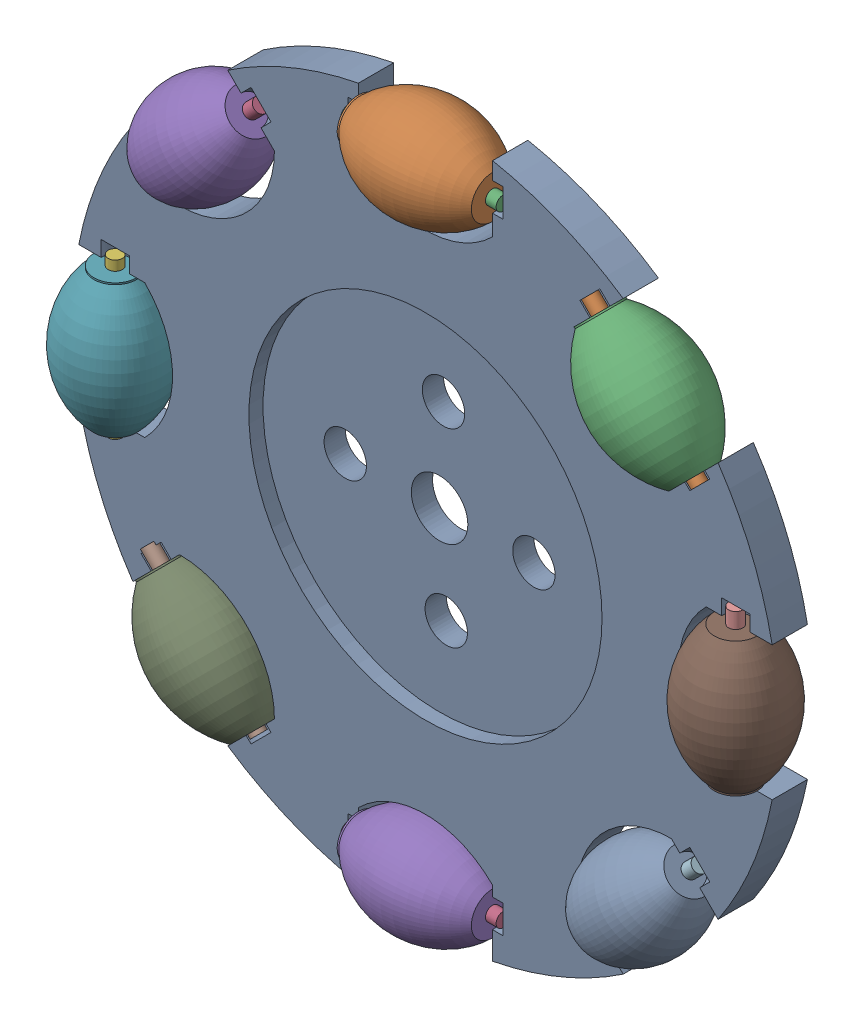
SolidWorks assembly Assem15, configuration Default. Lengths in mm.
Overall size (2608.01 2608.01 376.31).
17 component instances, 3 part files, 30 mates.
Components (placement in the parent):
- part1-1: part1 [Default] at (327.8823 573.5856 1240.6649) size (2493.73 2493.73 127)
- part3-1: part3 [Default] at (850.6704 2000.0817 1373.6453) x (1 0 0) z (0 -0.078483 0.996915) size (482.6 349.93 349.93)
- part4-1: part4 [Default] at (888.7704 1926.1491 1367.6649) x (0 0 1) z (-1 0 0) size (50.8 50.8 558.8)
- part4-2: part4 [Default] at (16.4737 1796.2945 1367.6649) x (0 0 1) z (-0.707107 -0.707107 0) size (50.8 50.8 558.8)
- part3-2: part3 [Default] at (-71.769 1812.6082 1373.6453) x (0.707107 0.707107 0) z (0.055496 -0.055496 0.996915) size (482.6 349.93 349.93)
- part4-3: part4 [Default] at (-504.4475 507.7487 1367.6649) x (0 0 1) z (0 1 0) size (50.8 50.8 558.8)
- part3-3: part3 [Default] at (-430.5148 548.9191 1373.6453) x (0 -1 0) z (-0.078483 0 0.996915) size (482.6 349.93 349.93)
- part4-4: part4 [Default] at (11.3101 -168.8495 1367.6649) x (0 0 1) z (-0.707107 0.707107 0) size (50.8 50.8 558.8)
- part3-4: part3 [Default] at (53.7091 -106.692 1373.6453) x (0.707107 -0.707107 0) z (-0.055496 -0.055496 0.996915) size (482.6 349.93 349.93)
- part4-5: part4 [Default] at (1723.1883 1087.6665 1367.6649) x (0 0 1) z (0 -1 0) size (50.8 50.8 558.8)
- part3-5: part3 [Default] at (1649.2557 1031.5191 1373.6453) x (0 1 0) z (0.078483 0 0.996915) size (482.6 349.93 349.93)
- part4-6: part4 [Default] at (1594.5242 218.244 1367.6649) x (0 0 1) z (-0.707107 -0.707107 0) size (50.8 50.8 558.8)
- part3-6: part3 [Default] at (1506.2815 234.5577 1373.6453) x (0.707107 0.707107 0) z (0.055496 -0.055496 0.996915) size (482.6 349.93 349.93)
- part4-7: part4 [Default] at (1597.3984 1401.1632 1367.6649) x (0 0 1) z (-0.707107 0.707107 0) size (50.8 50.8 558.8)
- part3-7: part3 [Default] at (1631.7596 1471.3585 1373.6453) x (0.707107 -0.707107 0) z (-0.055496 -0.055496 0.996915) size (482.6 349.93 349.93)
- part4-8: part4 [Default] at (888.7704 -305.5514 1367.6649) x (0 0 1) z (-1 0 0) size (50.8 50.8 558.8)
- part3-8: part3 [Default] at (850.6704 -231.6187 1373.6453) x (1 0 0) z (0 -0.078483 0.996915) size (482.6 349.93 349.93)
Mates (geometry in assembly coordinates):
- Concentric3: concentric aligned: cylinder of part1-1 through (888.7704 1924.1167 1367.6649) axis (1 0 0) radius 50.8; cylinder of part4-1 through (329.9704 1924.1167 1367.6649) axis (1 0 0) radius 25.4
- Coincident1: coincident anti-aligned: plane of part1-1 through (888.7704 1974.9167 1367.6649) normal (-1 0 0); plane of part4-1 through (888.7704 1924.1167 1367.6649) normal (1 0 0)
- Concentric4: concentric anti-aligned: cylinder of part3-1 through (393.4704 1924.1167 1367.6649) axis (-1 0 0) radius 25.4; cylinder of part4-1 through (329.9704 1924.1167 1367.6649) axis (1 0 0) radius 25.4
- Coincident2: coincident anti-aligned: plane of part1-1 through (368.0704 2037.0849 1367.6649) normal (1 0 0); plane of part3-1 through (368.0704 2000.0817 1373.6453) normal (-1 0 0)
- Concentric5: concentric anti-aligned: cylinder of part4-2 through (-377.2205 1399.7261 1367.6649) axis (0.707107 0.707107 0) radius 25.4; cylinder of part3-2 through (-341.3429 1435.6037 1367.6649) axis (-0.707107 -0.707107 0) radius 25.4
- Concentric6: concentric aligned: cylinder of part1-1 through (17.9108 1794.8574 1367.6649) axis (0.707107 0.707107 0) radius 50.8; cylinder of part4-2 through (-377.2205 1399.7261 1367.6649) axis (0.707107 0.707107 0) radius 25.4
- Coincident3: coincident anti-aligned: circle of part1-1; plane of part4-2 through (-377.2205 1399.7261 1367.6649) normal (-0.707107 -0.707107 0)
- Coincident4: coincident anti-aligned: plane of part1-1 through (-442.9217 1501.2615 1367.6649) normal (0.707107 0.707107 0); plane of part3-2 through (-413.0188 1471.3585 1373.6453) normal (-0.707107 -0.707107 0)
- Concentric7: concentric anti-aligned: cylinder of part4-3 through (-506.4798 1066.5487 1367.6649) axis (0 -1 0) radius 25.4; cylinder of part3-3 through (-506.4798 1006.1191 1367.6649) axis (0 1 0) radius 25.4
- Concentric8: concentric anti-aligned: cylinder of part1-1 through (-506.4798 1087.6665 1367.6649) axis (0 1 0) radius 50.8; cylinder of part4-3 through (-506.4798 1066.5487 1367.6649) axis (0 -1 0) radius 25.4
- Coincident5: coincident anti-aligned: plane of part1-1 through (-637.4954 548.9191 1367.6649) normal (0 1 0); plane of part3-3 through (-430.5148 548.9191 1373.6453) normal (0 -1 0)
- Concentric9: concentric anti-aligned: cylinder of part4-4 through (-385.2583 224.8447 1367.6649) axis (0.707107 -0.707107 0) radius 25.4; cylinder of part3-4 through (-323.2955 162.8819 1367.6649) axis (-0.707107 0.707107 0) radius 25.4
- Concentric10: concentric anti-aligned: cylinder of part1-1 through (-377.2205 216.8069 1367.6649) axis (-0.707107 0.707107 0) radius 50.8; cylinder of part4-4 through (-385.2583 224.8447 1367.6649) axis (0.707107 -0.707107 0) radius 25.4
- Coincident6: coincident anti-aligned: plane of part1-1 through (-101.672 -262.0731 1367.6649) normal (-0.707107 0.707107 0); plane of part3-4 through (53.7091 -106.692 1373.6453) normal (0.707107 -0.707107 0)
- Concentric11: concentric anti-aligned: cylinder of part4-5 through (1725.2206 528.8665 1367.6649) axis (0 1 0) radius 25.4; cylinder of part3-5 through (1725.2206 574.3191 1367.6649) axis (0 -1 0) radius 25.4
- Concentric12: concentric anti-aligned: cylinder of part4-6 through (1200.83 -178.3244 1367.6649) axis (0.707107 0.707107 0) radius 25.4; cylinder of part3-6 through (1959.0279 535.3617 1334.6261) axis (-0.707107 -0.707107 0) radius 25.4
- Concentric13: concentric anti-aligned: cylinder of part4-7 through (1200.83 1794.8574 1367.6649) axis (0.707107 -0.707107 0) radius 25.4; cylinder of part3-7 through (1254.755 1740.9324 1367.6649) axis (-0.707107 0.707107 0) radius 25.4
- Concentric14: concentric anti-aligned: cylinder of part4-8 through (329.9704 -307.5837 1367.6649) axis (1 0 0) radius 25.4; cylinder of part3-8 through (1881.6362 -323.7541 1365.3086) axis (-1 0 0) radius 25.4
- Concentric15: concentric aligned: cylinder of part1-1 through (1595.9613 1399.7261 1367.6649) axis (0.707107 -0.707107 0) radius 50.8; cylinder of part4-7 through (1200.83 1794.8574 1367.6649) axis (0.707107 -0.707107 0) radius 25.4
- Coincident7: coincident anti-aligned: plane of part1-1 through (1631.8823 1435.6471 1367.6649) normal (-0.707107 0.707107 0); plane of part4-7 through (1595.9613 1399.7261 1367.6649) normal (0.707107 -0.707107 0)
- Coincident8: coincident anti-aligned: plane of part1-1 through (1320.4128 1842.5112 1367.6649) normal (0.707107 -0.707107 0); plane of part3-7 through (1290.5098 1812.6082 1373.6453) normal (-0.707107 0.707107 0)
- Concentric16: concentric anti-aligned: cylinder of part1-1 through (1725.2206 528.8665 1367.6649) axis (0 -1 0) radius 50.8; cylinder of part4-5 through (1725.2206 528.8665 1367.6649) axis (0 1 0) radius 25.4
- Coincident9: coincident anti-aligned: plane of part1-1 through (1776.0206 528.8665 1367.6649) normal (0 1 0); circle of part4-5
- Coincident10: coincident anti-aligned: plane of part1-1 through (1856.2362 548.9191 1367.6649) normal (0 1 0); plane of part3-5 through (1649.2557 548.9191 1373.6453) normal (0 -1 0)
- Concentric17: concentric anti-aligned: cylinder of part1-1 through (1200.83 -178.3244 1367.6649) axis (-0.707107 -0.707107 0) radius 50.8; cylinder of part4-6 through (1200.83 -178.3244 1367.6649) axis (0.707107 0.707107 0) radius 25.4
- Coincident11: coincident anti-aligned: plane of part1-1 through (1236.751 -214.2454 1367.6649) normal (0.707107 0.707107 0); plane of part4-6 through (1200.83 -178.3244 1367.6649) normal (-0.707107 -0.707107 0)
- Coincident13: coincident anti-aligned: plane of part1-1 through (1320.4128 -262.0731 1367.6649) normal (0.707107 0.707107 0); plane of part3-6 through (1165.0317 -106.692 1373.6453) normal (-0.707107 -0.707107 0)
- Concentric18: concentric anti-aligned: cylinder of part1-1 through (329.9704 -307.5837 1367.6649) axis (-1 0 0) radius 50.8; cylinder of part4-8 through (329.9704 -307.5837 1367.6649) axis (1 0 0) radius 25.4
- Coincident14: coincident anti-aligned: plane of part1-1 through (329.9704 -358.3837 1367.6649) normal (1 0 0); plane of part4-8 through (329.9704 -307.5837 1367.6649) normal (-1 0 0)
- Coincident15: coincident anti-aligned: plane of part1-1 through (368.0704 -456.6467 1367.6649) normal (1 0 0); plane of part3-8 through (368.0704 -231.6187 1373.6453) normal (-1 0 0)
